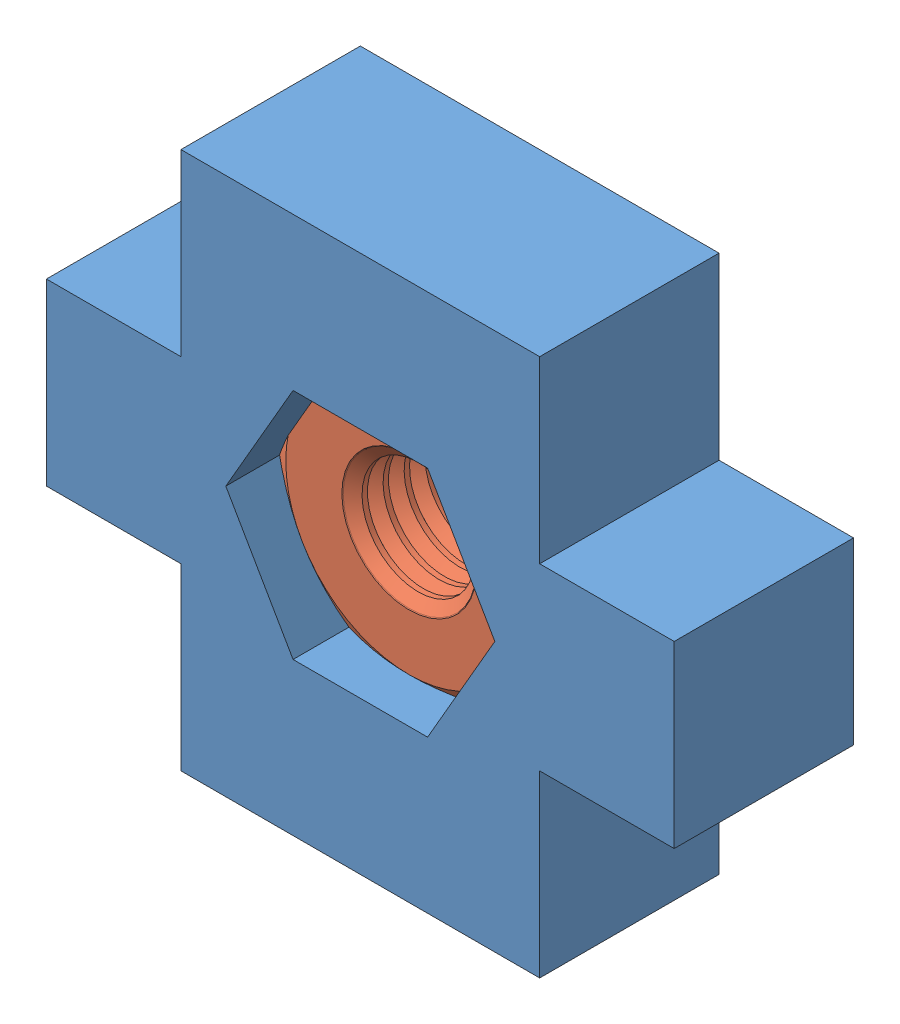
SolidWorks assembly fastenFlangeAssembled, configuration Default. Lengths in mm.
Overall size (14 12 4).
2 component instances, 2 part files, 3 mates.
Components (placement in the parent):
- BasePulleyInsidePalm-1: BasePulleyInsidePalm [Default] at (3.6005 5.4798 12.8446) size (14 12 4)
- hex nut style 1 gradeab_din-1: hex nut style 1 gradeab_din [Hexagon Nut ISO 4032 - M3 - D - S] at (7.6882 11.6317 15.8446) x (-0.866025 -0.5 0) z (0 0 1) size (5.5 6.35 2.4)
Mates (geometry in assembly coordinates):
- Coincident1: coincident anti-aligned: plane of BasePulleyInsidePalm-1 through (6.1005 8.8817 16.8446) normal (0 1 0); plane of hex nut style 1 gradeab_din-1 through (6.1005 8.8817 13.4446) normal (0 -1 0)
- Coincident2: coincident anti-aligned: plane of BasePulleyInsidePalm-1 through (4.6005 11.4798 16.8446) normal (0.866025 0.5 0); plane of hex nut style 1 gradeab_din-1 through (6.1005 8.8817 13.4446) normal (-0.866025 -0.5 0)
- Distance1: distance = 3 mm anti-aligned: plane of BasePulleyInsidePalm-1 through (3.6005 5.4798 12.8446) normal (0 0 -1); plane of hex nut style 1 gradeab_din-1 through (9.2759 8.8817 15.8446) normal (0 0 1)
